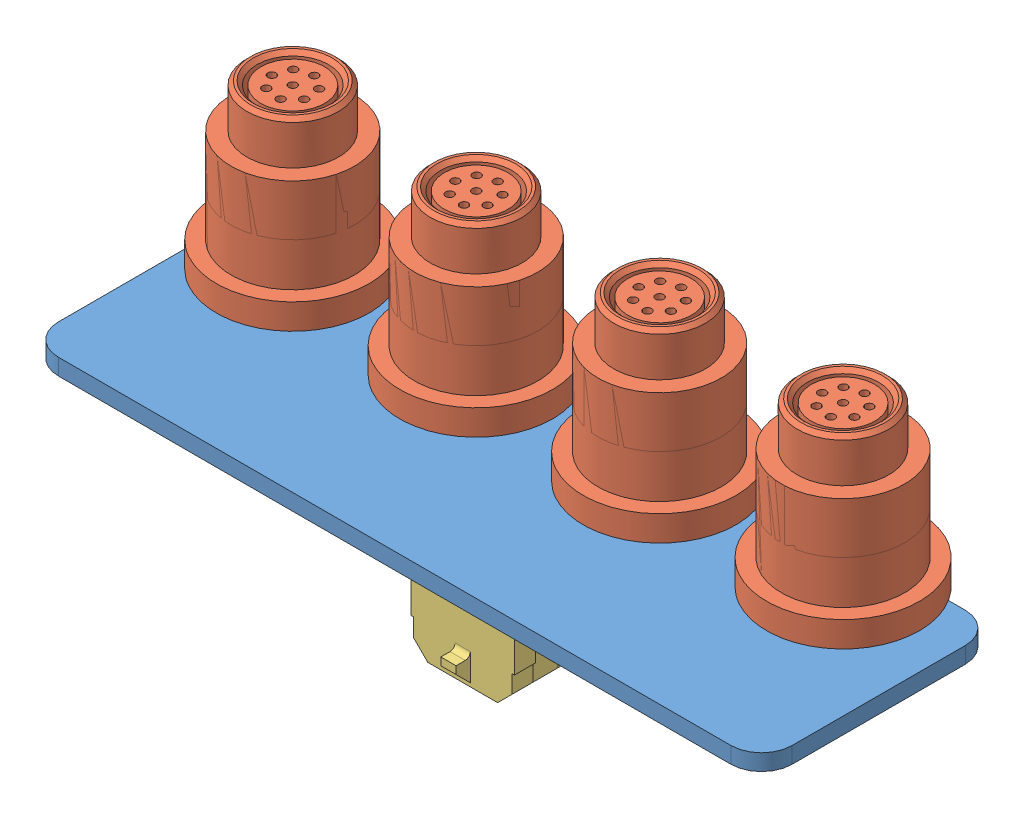
SolidWorks assembly Front_MCN_Breakout, configuration Default. Lengths in mm.
Overall size (74.76 30.56 26.38).
6 component instances, 3 part files, 11 mates.
Components (placement in the parent):
- FMCNB_PCB-1: FMCNB_PCB [Default] at (-41.0259 -0.8 18.9013) size (72 1.6 23)
- M8 Connector-1: M8 Connector [Default] at (22.9741 19.8 2.9013) x (-0.837169 0 -0.546944) z (-0.546944 0 0.837169) size (15 22 15)
- M8 Connector-2: M8 Connector [Default] at (4.9741 19.8 2.9013) x (-0.837169 0 -0.546944) z (-0.546944 0 0.837169) size (15 22 15)
- M8 Connector-3: M8 Connector [Default] at (-13.0259 19.8 2.9013) x (-0.837169 0 -0.546944) z (-0.546944 0 0.837169) size (15 22 15)
- Molex MicroFit 4pos vertical header - 43045-0418-1: Molex MicroFit 4pos vertical header - 43045-0418 [Default] at (-2.1009 -5.81 11.7213) x (1 0 0) z (0 -1 0) size (13.65 11.2 9.96)
- M8 Connector-4: M8 Connector [Default] at (-31.0259 19.8 2.9013) x (-0.837169 0 -0.546944) z (-0.546944 0 0.837169) size (15 22 15)
Mates (geometry in assembly coordinates):
- Coincident4: coincident anti-aligned: plane of FMCNB_PCB-1 through (-38.0259 0.8 15.9013) normal (0 1 0); plane of M8 Connector-1 through (22.7306 0.8 4.7654) normal (0 -1 0)
- Concentric1: concentric: point of FMCNB_PCB-1; cylinder of M8 Connector-1 through (22.9741 6.3 2.9013) axis (0 1 0) radius 6.05
- Coincident6: coincident anti-aligned: plane of FMCNB_PCB-1 through (-38.0259 0.8 15.9013) normal (0 1 0); plane of M8 Connector-2 through (4.7306 0.8 4.7654) normal (0 -1 0)
- Concentric2: concentric: point of FMCNB_PCB-1; cylinder of M8 Connector-2 through (4.9741 6.3 2.9013) axis (0 1 0) radius 6.05
- Coincident8: coincident anti-aligned: plane of FMCNB_PCB-1 through (-38.0259 0.8 15.9013) normal (0 1 0); plane of M8 Connector-3 through (-14.6352 0.8 3.8731) normal (0 -1 0)
- Concentric3: concentric: point of FMCNB_PCB-1; cylinder of M8 Connector-3 through (-13.0259 6.3 2.9013) axis (0 1 0) radius 6.05
- Coincident10: coincident anti-aligned: plane of FMCNB_PCB-1 through (-38.0259 -0.8 15.9013) normal (0 -1 0); plane of Molex MicroFit 4pos vertical header - 43045-0418-1 through (4.7241 -0.8 11.0863) normal (0 1 0)
- Distance2: distance = 28 mm aligned: plane of Molex MicroFit 4pos vertical header - 43045-0418-1 through (2.9741 -5.81 11.7213) normal (1 0 0); plane of FMCNB_PCB-1 through (30.9741 0.8 15.9013) normal (1 0 0)
- Distance3: distance = 3.75 mm aligned: plane of Molex MicroFit 4pos vertical header - 43045-0418-1 through (-6.9259 -0.85 15.1513) normal (0 0 1); plane of FMCNB_PCB-1 through (-38.0259 0.8 18.9013) normal (0 0 1)
- Coincident11: coincident anti-aligned: plane of FMCNB_PCB-1 through (-38.0259 0.8 15.9013) normal (0 1 0); plane of M8 Connector-4 through (-32.7891 0.8 2.249) normal (0 -1 0)
- Concentric4: concentric: point of FMCNB_PCB-1; cylinder of M8 Connector-4 through (-31.0259 14.4186 2.9013) axis (0 1 0) radius 0.4
